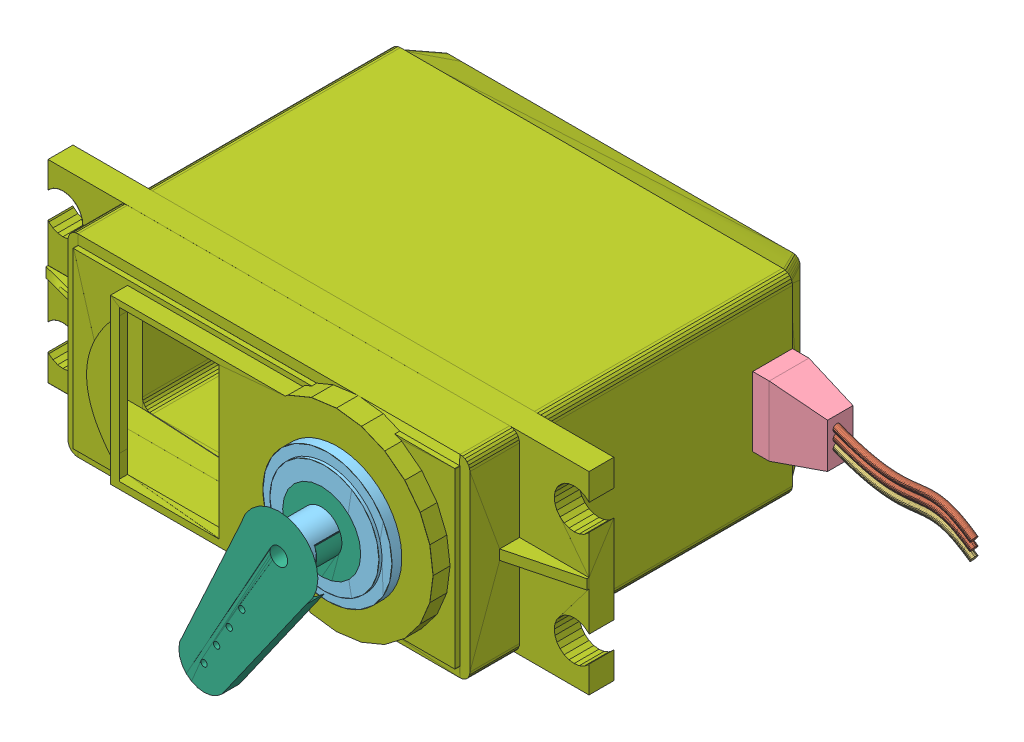
SolidWorks assembly Groupe_5, configuration Standard. Lengths in mm.
Overall size (1737.81 803.79 1114.29).
17 component instances, 8 part files, 0 mates.
Components (placement in the parent):
- Groupe_6-1: Groupe_6 [Standard] at (231.2826 -91.8146 -539.1957) size (90.82 90.82 35.9)
  - Groupe_7-1: Groupe_7 [Standard] at origin size (90.82 90.82 35.9)
- Groupe_6-2: Groupe_6 [Standard] at (231.2826 243.4654 -539.1957) size (90.82 90.82 35.9)
  - Groupe_7-1: Groupe_7 [Standard] at origin size (90.82 90.82 35.9)
- Groupe_4-1: Groupe_4 [Standard] at (603.3792 69.1313 -424.1632) x (0 0 -1) z (1 0 0) size (101.7 178.59 531.1)
  - Groupe_8-1: Groupe_8 [Standard] at (-10.9872 -23.8269 84.5461) x (0 1 0) z (-1 0 0) size (130.89 361.96 18.8)
    - Groupe_8-1-1: Groupe_8-1 [Standard] at origin size (109.27 361.96 18.8)
    - Groupe_8-2-1: Groupe_8-2 [Standard] at origin size (88.6 361.96 18.8)
  - Groupe_8-2: Groupe_8 [Standard] at (-10.9872 -23.8269 84.5461) x (0 1 0) z (-1 0 0) size (130.89 361.96 18.8)
  - Groupe_4-1: Groupe_4 [Standard] at origin size (101.7 177.9 175.36)
- Groupe_1-1: Groupe_1 [Standard] at (54.7631 76.0827 474.1397) size (330.2 330.2 134.62)
- Groupe_6-3: Groupe_6 [Standard] at (-586.5974 243.4654 -539.1957) size (90.82 90.82 35.9)
  - Groupe_7-1: Groupe_7 [Standard] at origin size (90.82 90.82 35.9)
- Groupe_6-4: Groupe_6 [Standard] at (-586.5974 -91.8146 -539.1957) size (90.82 90.82 35.9)
  - Groupe_7-1: Groupe_7 [Standard] at origin size (90.82 90.82 35.9)
- Group_5-1: Group_5 [Standard] at (-31.4317 -78.1778 502.3083) x (0.866859 -0.498554 0) z (0 0 1) size (230.22 579.89 109.68)
- Groupe_5-1: Groupe_5 [Standard] at origin size (1384.82 652.46 957.99)
